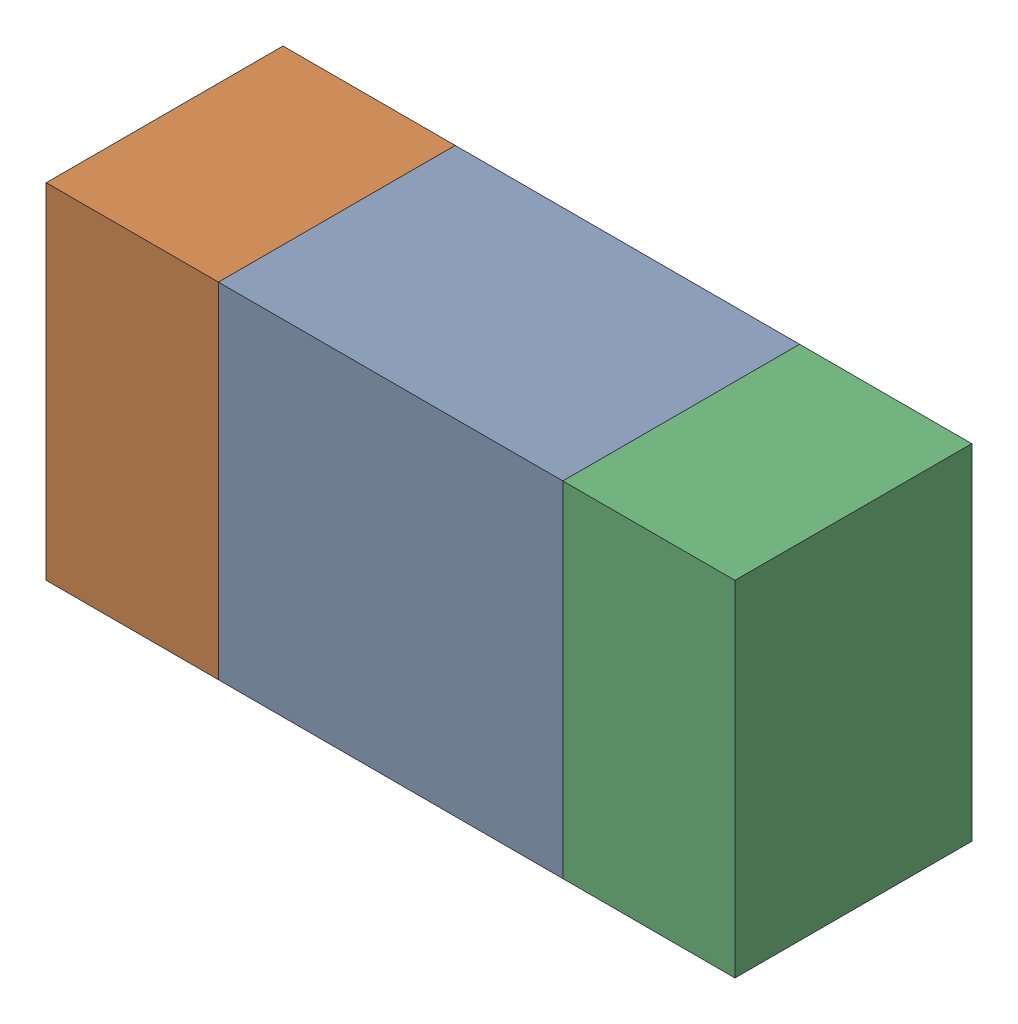
SolidWorks assembly R44, configuration ﾃﾞﾌｫﾙﾄ. Lengths in mm.
Overall size (1.6 0.8 0.55).
6 component instances, 2 part files, 0 mates.
Components (placement in the parent):
- 689261648-1: 689261648 [ﾃﾞﾌｫﾙﾄ] at (59 21.2001 -1.7503) size (0.8 0.8 0.55)
  - Extruded_33-1: Extruded_33 [ﾃﾞﾌｫﾙﾄ] at origin size (0.8 0.8 0.55)
- 689261512-1: 689261512 [ﾃﾞﾌｫﾙﾄ] at (58.3999 21.2001 -1.7503) size (0.4 0.8 0.55)
  - Extruded_32-1: Extruded_32 [ﾃﾞﾌｫﾙﾄ] at origin size (0.4 0.8 0.55)
- 689261512-2: 689261512 [ﾃﾞﾌｫﾙﾄ] at (59.5999 21.2001 -1.7503) size (0.4 0.8 0.55)
  - Extruded_32-1: Extruded_32 [ﾃﾞﾌｫﾙﾄ] at origin size (0.4 0.8 0.55)
